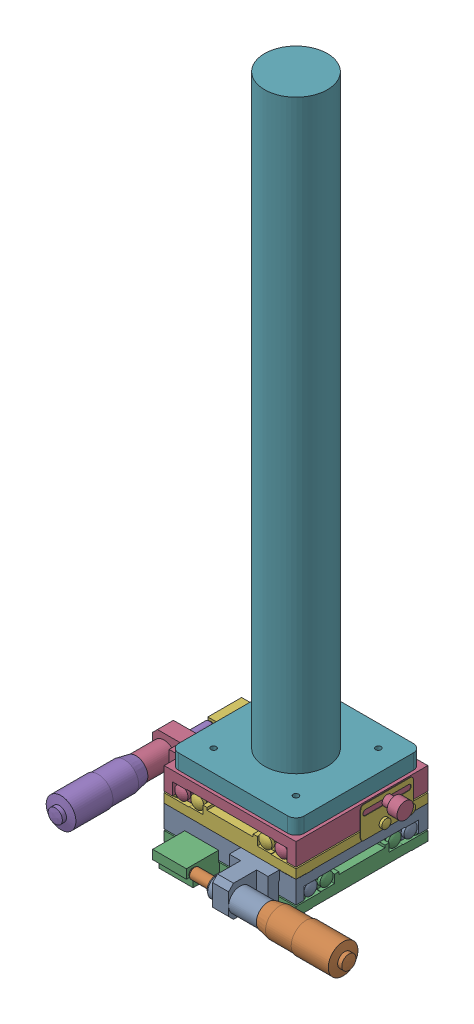
SolidWorks assembly z_shaft assembled_1, configuration Default. Lengths in mm.
Overall size (155.6 404.76 140.9).
3 component instances, 2 part files, 0 mates.
Components (placement in the parent):
- B11-80CZ.step_1-1: B11-80CZ.step_1 [Default] at (24.4701 -2.1391 -38.5314) x (1 0 0) z (0 1 0) size (130.2 117.3 20.22)
- B11-80CZ.step_1-2: B11-80CZ.step_1 [Default] at (24.4701 17.6609 -38.5314) x (0 0 1) z (0 1 0) size (130.2 117.3 20.22)
- z shaft_1-1: z shaft_1 [Default] at (-13.6299 37.6609 -0.4314) size (76.2 364.74 76.2)
